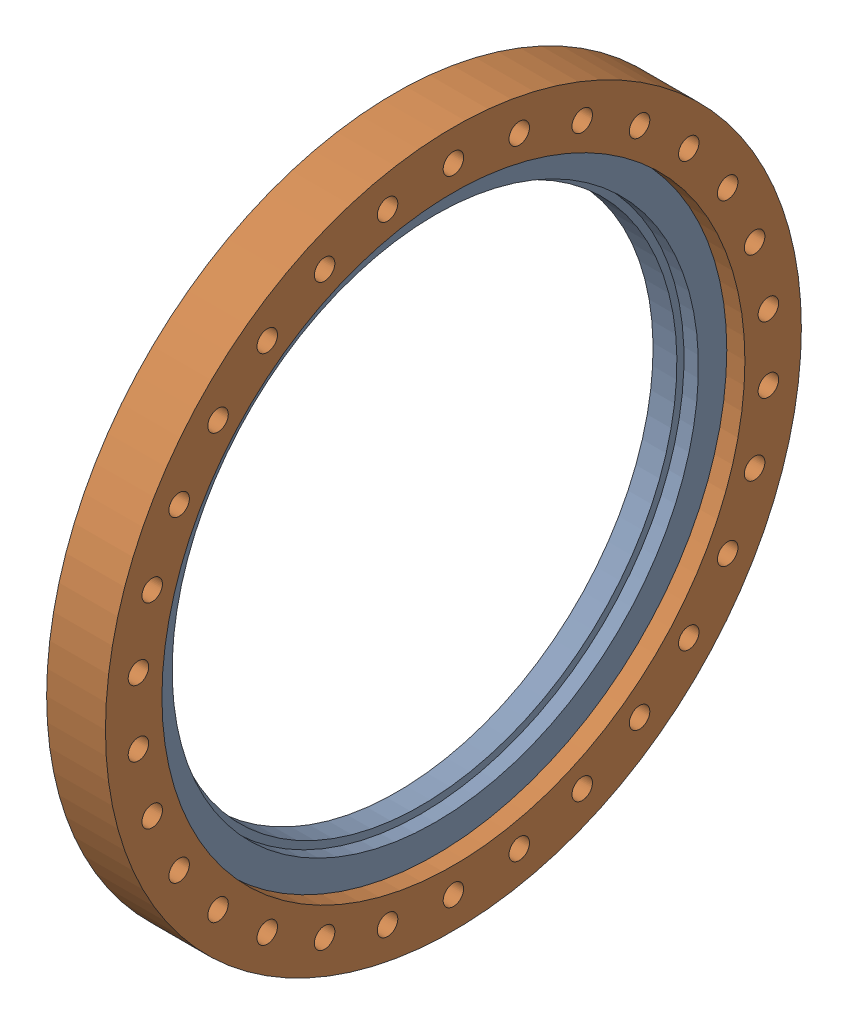
SolidWorks assembly 100035 (13.25 X 10.0 R), configuration Default. Lengths in mm.
Overall size (28.45 336.55 336.55).
2 component instances, 2 part files, 0 mates.
Components (placement in the parent):
- 100035 (13.25 X 10.0 INS)-1: 100035 (13.25 X 10.0 INS) [Default] at origin size (19.02 294.64 294.64)
- 100035 (13.25 X 10.0 REC)-1: 100035 (13.25 X 10.0 REC) [Default] at (-0.6604 0 0) size (28.45 336.55 336.55)
